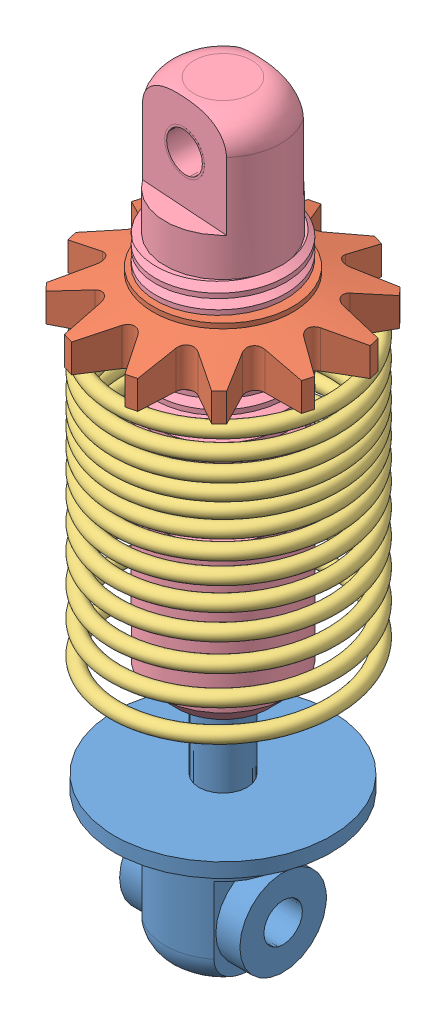
SolidWorks assembly Assem1, configuration Default. Lengths in mm.
Overall size (714.29 1103.21 714.29).
4 component instances, 4 part files, 6 mates.
Components (placement in the parent):
- base-1: base [Default] at (29.8336 212.376 608.1942) size (180 590.15 180)
- nut-1: nut [Default] at (29.8336 587.5119 608.1942) x (-0.518632 0 0.854998) z (-0.854998 0 -0.518632) size (520 118.96 520)
- spring-1: spring [Default] at (34.0688 567.6807 607.7424) x (-0.103864 0 -0.994591) z (-0.994591 0 0.103864) size (195.14 264.5 197.53)
- top rod-1: top rod [Default] at (29.798 1.8655 608.2355) x (0.067727 0 -0.997704) z (0.997704 0 0.067727) size (270.65 727.31 270.67)
Mates (geometry in assembly coordinates):
- Coincident1: coincident aligned: line of base-1 through (29.8336 522.5246 608.1942) axis (0 -1 0); line of top rod-1 through (29.8336 631.9929 608.1942) axis (0 -1 0)
- Concentric1: concentric aligned: cylinder of base-1 through (29.8336 522.5246 608.1942) axis (0 -1 0); cylinder of top rod-1 through (29.8336 631.9929 608.1942) axis (0 -1 0) radius 54
- Parallel1: parallel aligned: plane of base-1 through (29.8336 242.5246 608.1942) normal (0 1 0); plane of spring-1 through (34.0688 567.6807 607.7424) normal (0 1 0)
- Coincident8: coincident anti-aligned: line of nut-1 through (29.8336 587.5119 608.1942) axis (0 1 0); line of top rod-1 through (29.8336 631.9929 608.1942) axis (0 -1 0)
- Parallel5: parallel aligned: plane of base-1 through (29.8336 242.5246 608.1942) normal (0 1 0); plane of spring-1 through (34.0688 567.6807 607.7424) normal (0 1 0)
- Coincident10: coincident anti-aligned: plane of nut-1 through (29.8336 567.6807 608.1942) normal (0 -1 0); plane of spring-1 through (34.0688 567.6807 607.7424) normal (0 1 0)
